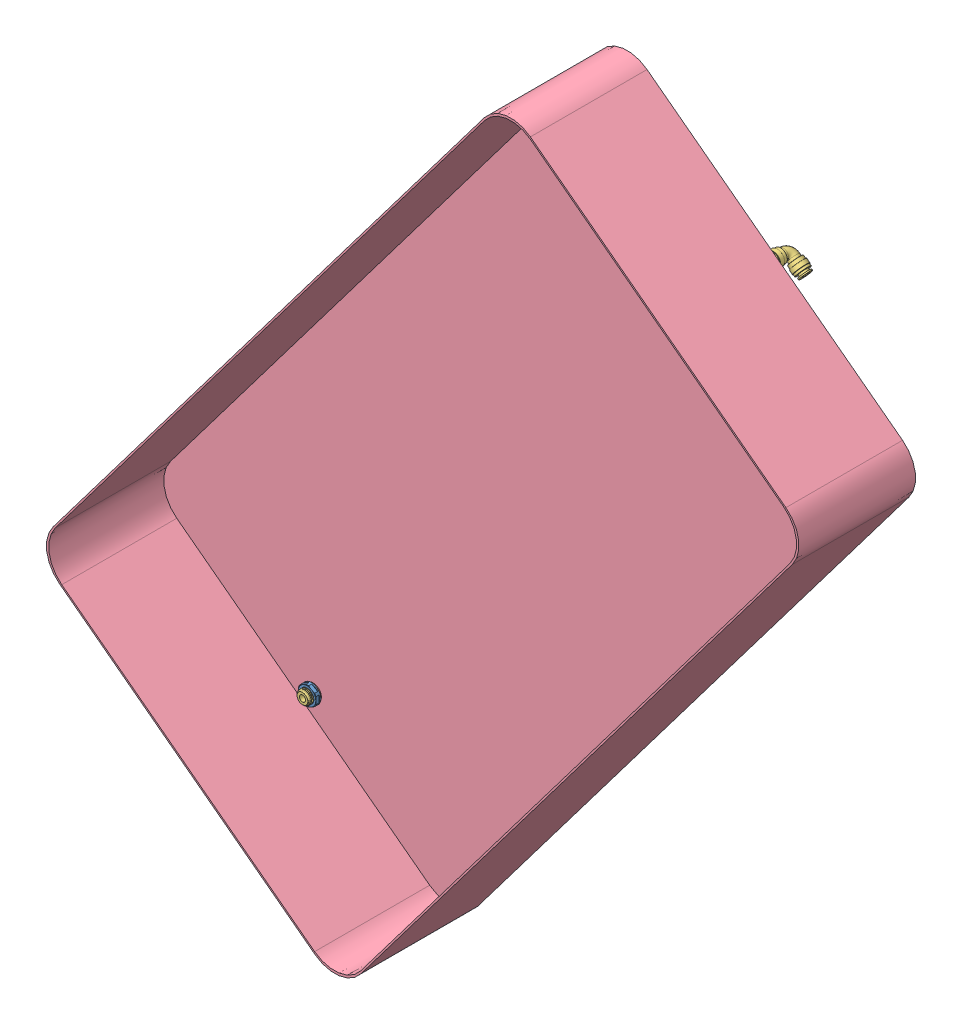
SolidWorks assembly tray_assembly, configuration Default. Lengths in mm.
Overall size (1203.96 1322.29 230.51).
9 component instances, 4 part files, 6 mates.
Components (placement in the parent):
- 90_assembly-1: 90_assembly [Default] at (-9.5526 -6.8374 33.696) size (52.61 48.36 69.22)
  - true_npt_nut-1: true_npt_nut [3185K112] at (-3.8428 13.2999 -10.4025) size (28.95 28.95 10.31)
  - hrd-050-gasket-1: hrd-050-gasket [Default] at (-3.8428 13.2999 -13.0187) x (0.930255 -0.366913 0) z (-0.366913 -0.930255 0) size (25.4 2.62 25.4)
  - through-wall-90-1: through-wall-90 [Default] at (-3.8428 13.2999 -15.5587) x (-0.797473 0.603354 0) z (-0.603354 -0.797473 0) size (46.99 69.22 25.08)
- tray_new-1: tray_new [Default] at (333.7203 465.2569 20.6772) x (0.603354 0.797473 0) z (0.797473 -0.603354 0) size (1206.5 180.34 596.9)
- 90_assembly-2: 90_assembly [Default] at (684.6789 910.7513 33.696) size (52.61 48.36 69.22)
  - true_npt_nut-1: true_npt_nut [3185K112] at (-3.8428 13.2999 -10.4025) size (28.95 28.95 10.31)
  - hrd-050-gasket-1: hrd-050-gasket [Default] at (-3.8428 13.2999 -13.0187) x (0.930255 -0.366913 0) z (-0.366913 -0.930255 0) size (25.4 2.62 25.4)
  - through-wall-90-1: through-wall-90 [Default] at (-3.8428 13.2999 -15.5587) x (-0.797473 0.603354 0) z (-0.603354 -0.797473 0) size (46.99 69.22 25.08)
Mates (geometry in assembly coordinates):
- Concentric1: concentric aligned: cylinder of 90_assembly-1/through-wall-90-1 through (-13.3954 6.4625 7.9772) axis (0 0 1) radius 11.557; cylinder of tray_new-1 through (-13.3954 6.4625 20.6772) axis (0 0 1) radius 11.1125
- Coincident1: coincident anti-aligned: plane of 90_assembly-1/through-wall-90-1 through (-13.3954 6.4625 18.1372) normal (0 0 1); plane of tray_new-1 through (333.7203 465.2569 18.1372) normal (0 0 -1)
- Coincident2: coincident: plane of tray_new-1 through (333.7203 465.2569 20.6772) normal (0 0 1); plane of 90_assembly-2/hrd-050-gasket-1 through (680.8361 924.0512 20.6772) normal (0 0 -1)
- Concentric2: concentric: circle of tray_new-1; circle of 90_assembly-2/through-wall-90-1
- Parallel1: parallel aligned: plane of 90_assembly-1/through-wall-90-1 through (18.2024 -5.6591 -20.4708) normal (0.797473 -0.603354 0); plane of tray_new-1 through (207.7528 -195.89 198.4772) normal (0.797473 -0.603354 0)
- Parallel2: parallel aligned: plane of tray_new-1 through (207.7528 -195.89 198.4772) normal (0.797473 -0.603354 0); plane of 90_assembly-2/through-wall-90-1 through (712.4338 911.9296 -20.4708) normal (0.797473 -0.603354 0)
